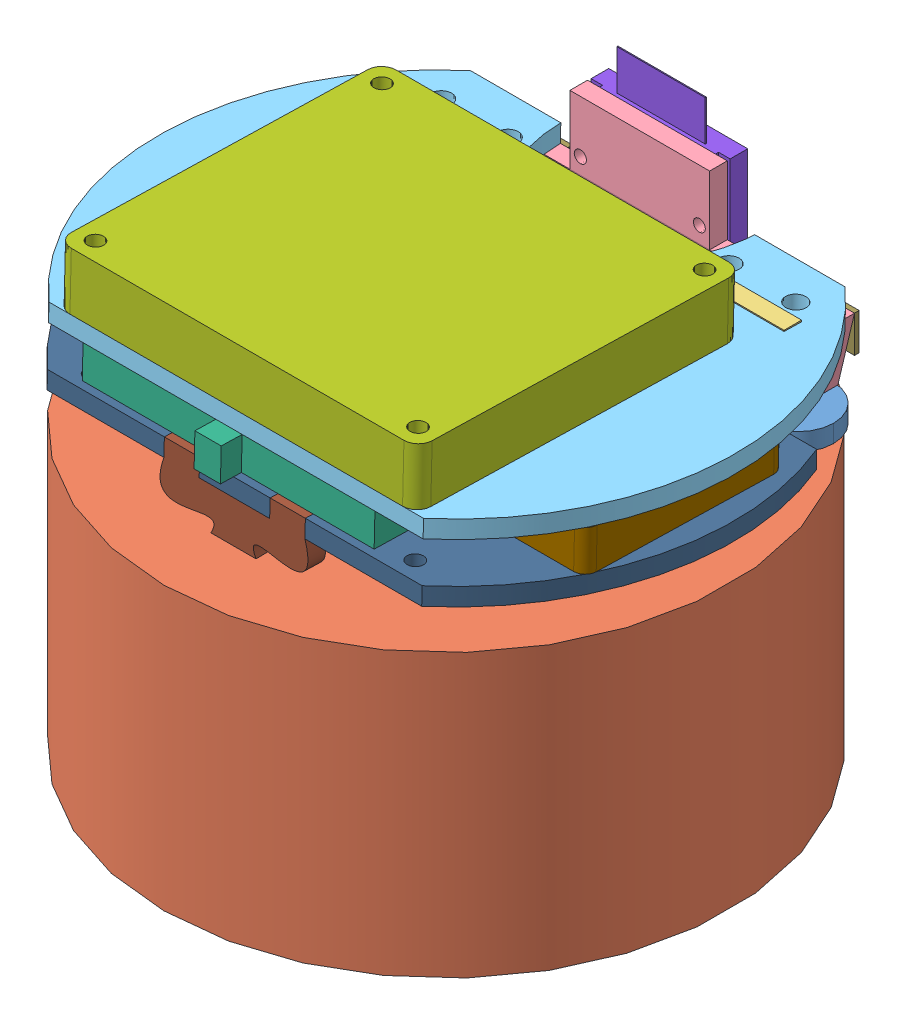
SolidWorks assembly Assem1, configuration Default. Lengths in mm.
Overall size (102.91 86.97 101.6).
15 component instances, 12 part files, 31 mates.
Components (placement in the parent):
- bottom-1: bottom [Default] at (-15.7116 38.5434 67.7868) size (76.2 3.17 12.7)
- shittyrobot-1: shittyrobot [Default] at (22.2641 -12.2566 93.0635) size (101.6 52.39 101.6)
- middle-3: middle [Default] at (-10.1236 54.4184 64.6118) size (71.02 19.56 3.17)
- camera mount-1: camera mount [Default] at (-10.1236 54.4184 55.0868) size (71.02 36.17 3.17)
- new base-1: new base [Default] at (22.3808 55.3475 93.0535) x (1 0 0) z (0 0.024464 0.999701) size (102.91 3.17 75.96)
- battery-1: battery [Default] at (37.5842 49.6119 98.5134) x (1 0 0) z (0 0.024464 0.999701) size (52.58 5.87 63.08)
- raspi-1: raspi [Default] at (55.908 68.3444 79.073) x (1 0 0) z (0 -0.024464 -0.999701) size (65 10.16 58.52)
- camera-1: camera [Default] at (9.1033 41.855 54.528) x (-1 0 0) z (0 0 -1) size (25.04 31.19 7.67)
- power circuit-1: power circuit [Default] at (59.8249 46.4301 23.5151) x (0 -0.024464 -0.999701) z (1 0 0) size (36.04 7.21 33.2)
- battery base-1: battery base [Default] at (22.3808 44.962 93.3077) x (1 0 0) z (0 0.024464 0.999701) size (102.91 3.17 58.25)
- lil nub-1: lil nub [Default] at (76.2529 13.6286 128.8879) x (1 0 0) z (0 0.024464 0.999701) size (27.51 12.34 3.17)
- hinge leaf-1: hinge leaf [Default] at (-13.1208 47.8144 54.2486) size (19.38 6.6 0.84)
- hinge leaf-2: hinge leaf [Default] at (38.5174 47.8144 54.2486) size (19.38 6.6 0.84)
- hinge leaf-3: hinge leaf [Default] at (38.5287 53.8321 65.3904) x (1 0 0) z (0 0.999701 -0.024464) size (19.38 6.6 0.84)
- hinge leaf-4: hinge leaf [Default] at (-13.1018 54.5127 58.942) x (1 0 0) z (0 -0.999701 0.024464) size (19.38 6.6 0.84)
Mates (geometry in assembly coordinates):
- Coincident11: coincident anti-aligned: plane of bottom-1 through (-15.7116 38.5434 67.7868) normal (0 -1 0); plane of shittyrobot-1 through (22.2641 38.5434 93.0635) normal (0 1 0)
- Coincident12: coincident anti-aligned: plane of bottom-1 through (-15.7116 41.7184 67.7868) normal (0 1 0); plane of middle-3 through (-10.1236 41.7184 67.7868) normal (0 -1 0)
- Coincident13: coincident anti-aligned: plane of bottom-1 through (44.6134 38.5434 67.7868) normal (-1 0 0); plane of middle-3 through (44.6134 54.4184 67.7868) normal (1 0 0)
- Coincident14: coincident anti-aligned: plane of bottom-1 through (6.5134 38.5434 64.6118) normal (0 0 1); plane of middle-3 through (-10.1236 54.4184 64.6118) normal (0 0 -1)
- Coincident15: coincident anti-aligned: plane of bottom-1 through (-15.7116 41.7184 67.7868) normal (0 1 0); plane of camera mount-1 through (-10.1236 41.7184 58.2618) normal (0 -1 0)
- Coincident16: coincident anti-aligned: plane of bottom-1 through (38.2634 38.5434 58.2618) normal (0 0 -1); plane of camera mount-1 through (-10.1236 54.4184 58.2618) normal (0 0 1)
- Coincident17: coincident anti-aligned: plane of bottom-1 through (6.5134 38.5434 55.0868) normal (-1 0 0); plane of camera mount-1 through (6.5134 54.4184 58.2618) normal (1 0 0)
- Coincident27: coincident anti-aligned: plane of camera mount-1 through (-10.1236 54.4184 55.0868) normal (0 0 -1); plane of camera-1 through (9.1033 41.855 55.0868) normal (0 0 1)
- Coincident32: coincident aligned: line of camera mount-1 through (34.9741 66.7184 55.0868) axis (-1 0 0); line of camera-1 through (32.8475 66.7184 55.0868) axis (-1 0 0)
- Coincident34: coincident aligned: line of camera mount-1 through (-13.1208 54.4184 55.0868) axis (1 0 0); line of new base-1 through (-11.358 54.4184 55.0868) axis (1 0 0)
- Coincident36: coincident anti-aligned: plane of new base-1 through (22.3808 58.5215 92.9759) normal (0 0.999701 -0.024464); plane of raspi-1 through (55.908 58.1874 79.3215) normal (0 -0.999701 0.024464)
- Coincident41: coincident anti-aligned: plane of battery-1 through (37.5842 55.4776 98.3699) normal (0 0.999701 -0.024464); plane of new base-1 through (22.3808 55.3475 93.0535) normal (0 -0.999701 0.024464)
- Coincident42: coincident anti-aligned: plane of new base-1 through (22.3808 55.3475 93.0535) normal (0 -0.999701 0.024464); plane of power circuit-1 through (59.8249 53.6415 23.3386) normal (0 0.999701 -0.024464)
- Parallel5: parallel anti-aligned: line of raspi-1 through (54.8801 58.0811 74.9777) axis (0 0.024464 0.999701); line of power circuit-1 through (69.1816 55.8289 112.7283) axis (0 -0.024464 -0.999701)
- Coincident45: coincident aligned: line of new base-1 through (56.1196 59.4506 130.9426) axis (-1 0 0); line of raspi-1 through (52.3401 59.4506 130.9426) axis (-1 0 0)
- Coincident46: coincident anti-aligned: line of new base-1 through (56.1196 56.2766 131.0203) axis (-1 0 0); line of battery-1 through (23.5205 56.2766 131.0203) axis (1 0 0)
- Distance5: distance = 10.16 mm: line of raspi-1 through (22.3808 68.1759 72.1899) axis (0 0.024464 0.999701); line of new base-1 through (22.3808 58.0274 72.7838) axis (0 0.024464 0.999701)
- Coincident57: coincident anti-aligned: plane of battery-1 through (47.4392 55.4776 98.3699) normal (1 0 0); plane of power circuit-1 through (47.4392 55.8787 114.7596) normal (-1 0 0)
- Coincident58: coincident anti-aligned: plane of power circuit-1 through (59.8249 46.4301 23.5151) normal (0 -0.999701 0.024464); plane of battery base-1 through (22.3808 48.136 93.23) normal (0 0.999701 -0.024464)
- Concentric1: concentric aligned: circle of new base-1; circle of battery base-1
- Coincident60: coincident aligned: plane of battery base-1 through (-30.7603 45.8911 131.2744) normal (0 0.024464 0.999701); plane of lil nub-1 through (76.2529 13.7063 132.062) normal (0 0.024464 0.999701)
- Coincident61: coincident aligned: plane of battery base-1 through (22.3808 48.136 93.23) normal (0 0.999701 -0.024464); plane of lil nub-1 through (76.2529 49.0651 131.1967) normal (0 0.999701 -0.024464)
- Coincident62: coincident anti-aligned: plane of battery base-1 through (28.7308 49.0651 131.1967) normal (1 0 0); plane of lil nub-1 through (28.7308 13.7063 132.062) normal (-1 0 0)
- Distance7: distance = 1.778 mm: point of camera mount-1; point of new base-1
- Coincident64: coincident anti-aligned: plane of camera mount-1 through (-10.1236 54.4184 55.0868) normal (0 0 -1); plane of hinge leaf-1 through (-13.1208 47.8144 55.0868) normal (0 0 1)
- Coincident65: coincident anti-aligned: plane of camera mount-1 through (-10.1236 54.4184 55.0868) normal (0 0 -1); plane of hinge leaf-2 through (38.5174 47.8144 55.0868) normal (0 0 1)
- Coincident66: coincident: point of camera mount-1; point of hinge leaf-2
- Coincident67: coincident: point of camera mount-1; point of hinge leaf-1
- Coincident68: coincident anti-aligned: plane of new base-1 through (22.3808 55.3475 93.0535) normal (0 -0.999701 0.024464); plane of hinge leaf-4 through (-13.1018 54.5127 58.942) normal (0 0.999701 -0.024464)
- Coincident74: coincident anti-aligned: plane of new base-1 through (22.3808 55.3475 93.0535) normal (0 -0.999701 0.024464); plane of hinge leaf-3 through (38.5287 54.67 65.3699) normal (0 0.999701 -0.024464)
- Parallel8: parallel aligned: line of middle-3 through (57.8976 58.1014 67.7868) axis (-1 0 0); line of battery base-1 through (68.9593 44.466 73.0386) axis (-1 0 0)
